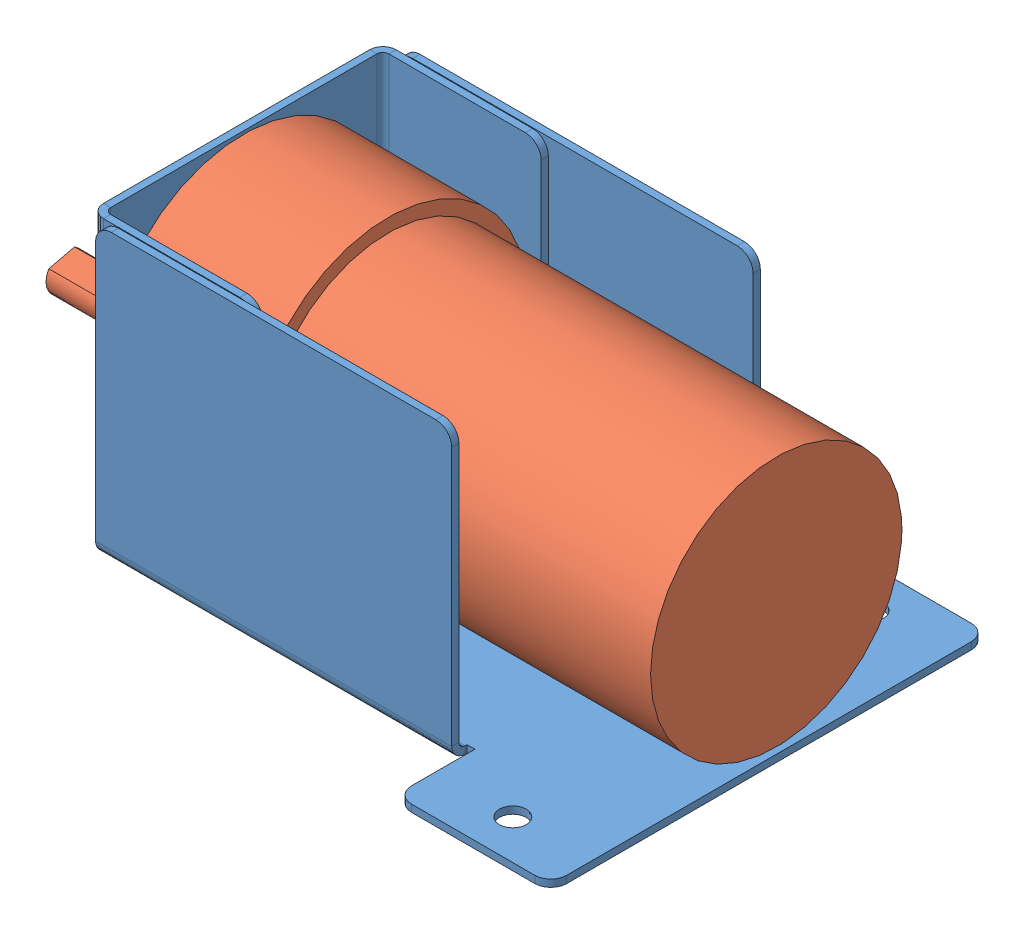
SolidWorks assembly BarbCole Motor with Fixture, configuration Default. Lengths in mm.
Overall size (89.87 36.41 55.14).
2 component instances, 2 part files, 2 mates.
Components (placement in the parent):
- BarbCole Geared Fixture-1: BarbCole Geared Fixture [Default] at (-41.6291 -27.9181 27.027) size (67.26 36.41 55.14)
- Motor BarbCole Geared-1: Motor BarbCole Geared [Default] at (-22.4819 -10.3495 9.4562) size (89.87 35.14 35.14)
Mates (geometry in assembly coordinates):
- Concentric1: concentric aligned: circle of BarbCole Geared Fixture-1; circle of Motor BarbCole Geared-1
- Coincident2: coincident anti-aligned: plane of BarbCole Geared Fixture-1 through (-40.7191 -27.9181 27.027) normal (1 0 0); plane of Motor BarbCole Geared-1 through (-40.7191 -10.3495 9.4562) normal (-1 0 0)
